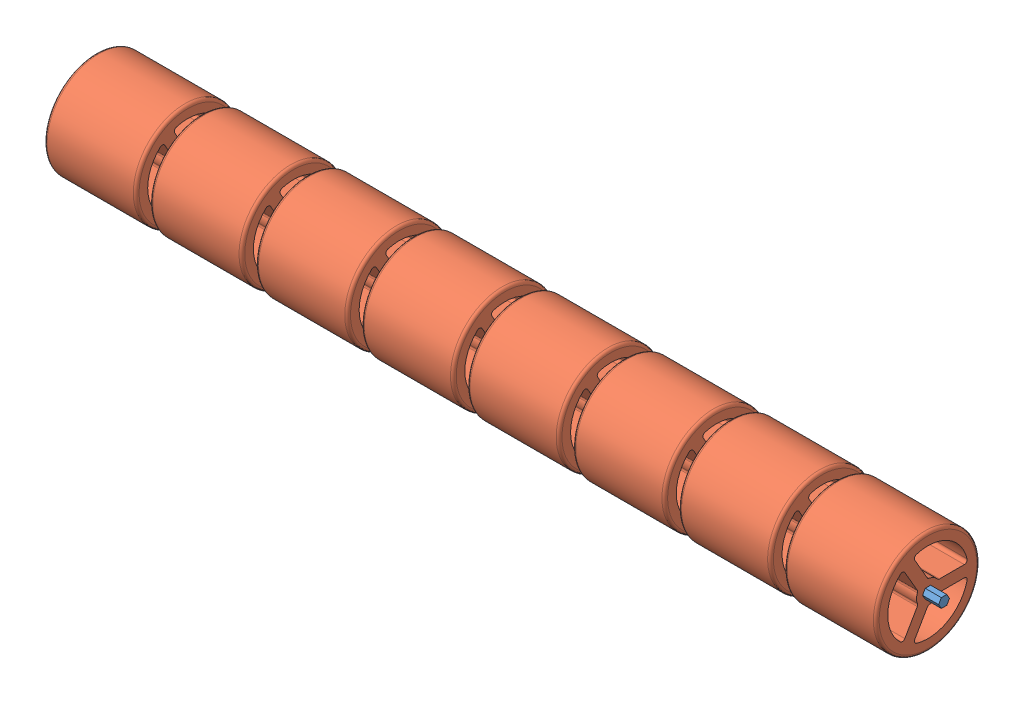
SolidWorks assembly Assem3, configuration Default. Lengths in mm.
Overall size (238.76 28.57 28.57).
9 component instances, 2 part files, 3 mates.
Components (placement in the parent):
- Drive Shaft-1: Drive Shaft [Default] at origin size (238.76 2.6 3)
- Drive Wheel-1: Drive Wheel [Default] at (-14.605 0 0) size (25.4 28.57 28.57)
- Drive Wheel-2: Drive Wheel [Default] at (-43.815 0 0) size (25.4 28.57 28.57)
- Drive Wheel-3: Drive Wheel [Default] at (-73.025 0 0) size (25.4 28.57 28.57)
- Drive Wheel-4: Drive Wheel [Default] at (-102.235 0 0) size (25.4 28.57 28.57)
- Drive Wheel-5: Drive Wheel [Default] at (14.605 0 0) size (25.4 28.57 28.57)
- Drive Wheel-6: Drive Wheel [Default] at (43.815 0 0) size (25.4 28.57 28.57)
- Drive Wheel-7: Drive Wheel [Default] at (73.025 0 0) size (25.4 28.57 28.57)
- Drive Wheel-8: Drive Wheel [Default] at (102.235 0 0) size (25.4 28.57 28.57)
Mates (geometry in assembly coordinates):
- Concentric1: concentric anti-aligned: line of Drive Shaft-1 through (-131.318 0 0) axis (1 0 0); cylinder of Drive Wheel-1 through (-1.905 0 0) axis (-1 0 0) radius 14.2875
- Distance1: distance = 14.605 mm aligned: plane of assembly through (0 0 0) normal (1 0 0); plane of Drive Wheel-1 through (-14.605 0 0) normal (1 0 0)
- Coincident2: coincident aligned: plane of Drive Wheel-1 through (-14.605 0 0) normal (0 1 0); plane of assembly through (0 0 0) normal (0 1 0)
